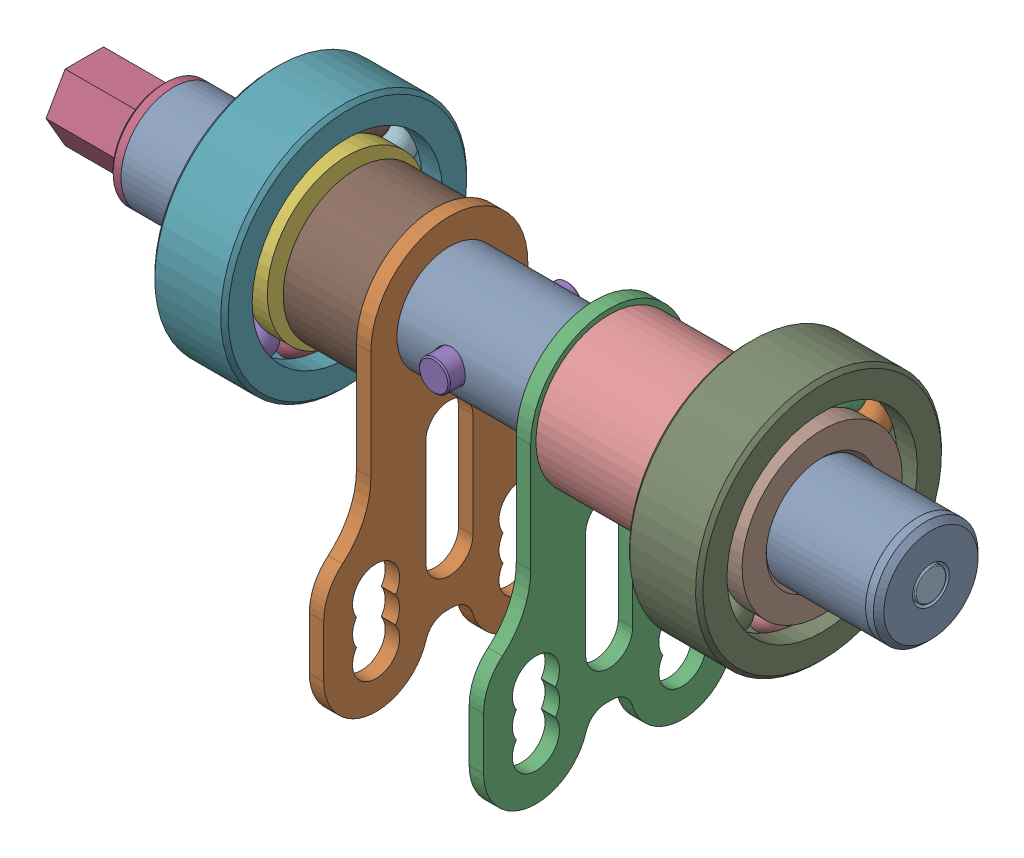
SolidWorks assembly Rotating_Body, configuration 默认. Lengths in mm.
Overall size (161.8 93.09 66.18).
13 component instances, 9 part files, 10 mates.
Components (placement in the parent):
- Pinned_Shaft-1: Pinned_Shaft [默认] at (-0.7395 2.9321 -0.4593) size (159.3 75 48)
  - TopKart_Shaft-1: TopKart_Shaft [默认] at (-31.3967 25.9787 2.6437) size (142.3 75 48)
    - steering shaft-1: steering shaft [默认] at origin size (142.3 20 20)
    - tie_rod_turner-1: tie_rod_turner [默认] at (14.7 0 0) x (0 0 -1) z (1 0 0) size (48 75 2.75)
    - tie_rod_turner-2: tie_rod_turner [默认] at (45.25 0 0) x (0 0 -1) z (1 0 0) size (48 75 2.75)
  - hexagonal shaft-2: hexagonal shaft [默认] at (-66.6967 25.9787 2.6437) x (1 0 0) z (0 -1 -0.001) size (92 20 20)
  - Hexagonal_shaft_pin-1: Hexagonal_shaft_pin [Default] at (-3.9967 25.9658 15.5775) x (0.111657 -0.993746 -0.000993) z (-0.993747 -0.111657 -0.000112) size (5.9 25.6 5.9)
- deep groove bearing 6204-3: deep groove bearing 6204 [5972K105] at (-41.1693 28.9108 2.1844) x (0 -0.638224 -0.76985) z (-1 0 0) size (47 47 14)
- deep groove bearing 6204-4: deep groove bearing 6204 [5972K105] at (49.5736 28.9108 2.1844) x (0 0.984078 -0.177735) z (1 0 0) size (47 47 14)
- sleeve back-2: sleeve back [默认] at (15.8638 28.9108 2.1844) x (0 -0.867667 -0.497146) z (1 0 0) size (28 28 25)
- sleeve front-2: sleeve front [默认] at (-32.4362 28.9108 2.1844) x (0 0 -1) z (1 0 0) size (28 28 15)
- AS5047P magnet-2: AS5047P magnet [Default] at (77.3638 28.9108 2.1844) x (0 0.521821 0.853055) z (0 -0.853055 0.521821) size (6 2.5 6)
- magnet mount-2: magnet mount [默认] at (74.8638 28.9108 2.1844) x (1 0 0) z (0 -0.396465 0.91805) size (22.5 20 20)
Mates (geometry in assembly coordinates):
- Concentric3: concentric aligned: circle of Pinned_Shaft-1/TopKart_Shaft-1/steering shaft-1; circle of deep groove bearing 6204-4
- Concentric4: concentric aligned: circle of Pinned_Shaft-1/TopKart_Shaft-1/steering shaft-1; circle of deep groove bearing 6204-3
- Concentric5: concentric aligned: circle of Pinned_Shaft-1/TopKart_Shaft-1/steering shaft-1; circle of sleeve back-2
- Concentric6: concentric anti-aligned: circle of Pinned_Shaft-1/TopKart_Shaft-1/steering shaft-1; circle of sleeve front-2
- Coincident5: coincident anti-aligned: plane of Pinned_Shaft-1/TopKart_Shaft-1/tie_rod_turner-2 through (15.8638 -25.0892 1.6008) normal (1 0 0); plane of sleeve back-2 through (15.8638 28.9108 2.1844) normal (-1 0 0)
- Coincident6: coincident anti-aligned: plane of Pinned_Shaft-1/TopKart_Shaft-1/tie_rod_turner-1 through (-17.4362 -25.0892 1.6008) normal (-1 0 0); plane of sleeve front-2 through (-17.4362 28.9108 2.1844) normal (1 0 0)
- Concentric7: concentric aligned: circle of Pinned_Shaft-1/TopKart_Shaft-1/steering shaft-1; circle of magnet mount-2
- Coincident9: coincident anti-aligned: plane of Pinned_Shaft-1/TopKart_Shaft-1/steering shaft-1 through (74.8638 28.9108 2.1844) normal (1 0 0); plane of magnet mount-2 through (74.8638 28.9108 2.1844) normal (-1 0 0)
- Concentric8: concentric anti-aligned: circle of AS5047P magnet-2; circle of magnet mount-2
- Coincident10: coincident anti-aligned: plane of AS5047P magnet-2 through (74.8638 28.9108 2.1844) normal (-1 0 0); plane of magnet mount-2 through (74.8638 28.9108 2.1844) normal (1 0 0)
